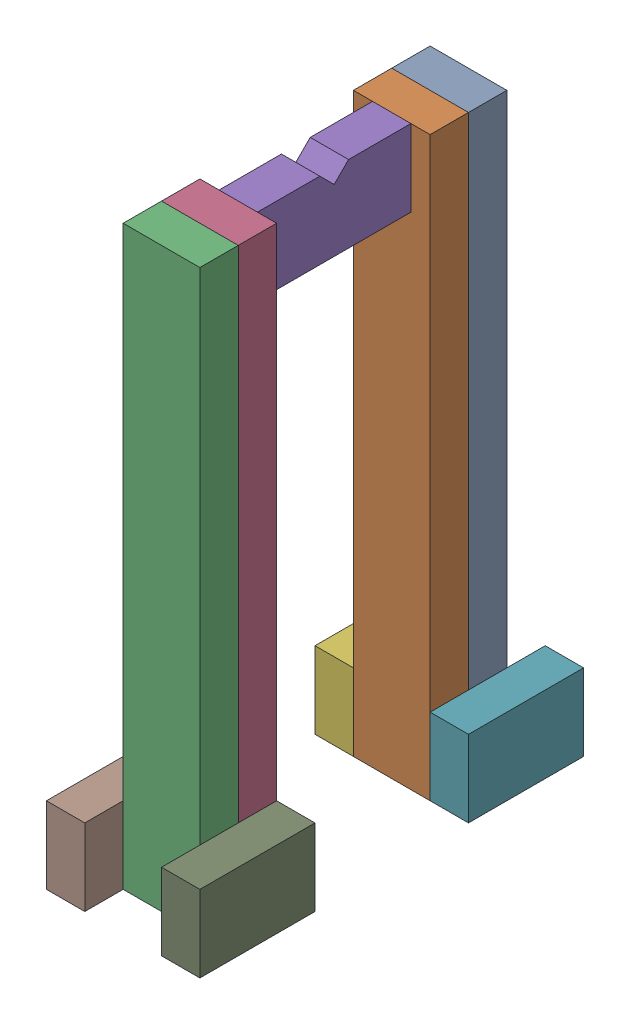
SolidWorks assembly RearRollHoop_CupJig, configuration Default. Lengths in mm.
Overall size (203.2 763.79 508).
9 component instances, 3 part files, 24 mates.
Components (placement in the parent):
- 30.028_Leg_CupJig_002-1: 30.028_Leg_CupJig_002 [Default] at origin size (101.6 763.79 50.8)
- 30.028_Leg_CupJig_002-2: 30.028_Leg_CupJig_002 [Default] at (0 0 50.8) size (101.6 763.79 50.8)
- 30.028_Leg_CupJig_002-3: 30.028_Leg_CupJig_002 [Default] at (0 0 355.6) size (101.6 763.79 50.8)
- 30.028_Leg_CupJig_002-4: 30.028_Leg_CupJig_002 [Default] at (0 0 304.8) size (101.6 763.79 50.8)
- 30.028_Cup_CupJig_002-1: 30.028_Cup_CupJig_002 [Default] at (50.8 662.194 279.4) x (0 0 -1) z (1 0 0) size (203.2 101.6 50.8)
- LegBase_CupJig_002-1: LegBase_CupJig_002 [Default] at (-25.4 0 -76.2) x (0 0 1) z (-1 0 0) size (152.4 101.6 50.8)
- LegBase_CupJig_002-2: LegBase_CupJig_002 [Default] at (127 0 76.2) x (0 0 -1) z (1 0 0) size (152.4 101.6 50.8)
- LegBase_CupJig_002-3: LegBase_CupJig_002 [Default] at (-25.4 0 431.8) x (0 0 -1) z (1 0 0) size (152.4 101.6 50.8)
- LegBase_CupJig_002-4: LegBase_CupJig_002 [Default] at (127 0 279.4) x (0 0 1) z (-1 0 0) size (152.4 101.6 50.8)
Mates (geometry in assembly coordinates):
- Coincident1: coincident anti-aligned: plane of 30.028_Leg_CupJig_002-1 through (0 0 25.4) normal (0 0 1); plane of 30.028_Leg_CupJig_002-2 through (0 0 25.4) normal (0 0 -1)
- Coincident2: coincident aligned: plane of 30.028_Leg_CupJig_002-1 through (101.6 0 25.4) normal (1 0 0); plane of 30.028_Leg_CupJig_002-2 through (101.6 0 76.2) normal (1 0 0)
- Coincident3: coincident aligned: plane of 30.028_Leg_CupJig_002-1 through (0 763.794 25.4) normal (0 1 0); plane of 30.028_Leg_CupJig_002-2 through (0 763.794 76.2) normal (0 1 0)
- Coincident4: coincident anti-aligned: plane of 30.028_Leg_CupJig_002-2 through (0 0 76.2) normal (0 0 1); plane of 30.028_Cup_CupJig_002-1 through (76.2 662.194 76.2) normal (0 0 -1)
- Width1: width anti-aligned: plane of 30.028_Leg_CupJig_002-2 through (101.6 0 76.2) normal (1 0 0); plane of 30.028_Cup_CupJig_002-1 through (0 0 76.2) normal (-1 0 0); plane of 30.028_Leg_CupJig_002-2 through (25.4 662.194 279.4) normal (-1 0 0); plane of 30.028_Cup_CupJig_002-1 through (76.2 662.194 279.4) normal (1 0 0)
- Coincident5: coincident aligned: plane of 30.028_Leg_CupJig_002-2 through (0 763.794 76.2) normal (0 1 0); plane of 30.028_Cup_CupJig_002-1 through (76.2 763.794 158.75) normal (0 1 0)
- Coincident6: coincident anti-aligned: plane of 30.028_Leg_CupJig_002-3 through (0 0 330.2) normal (0 0 -1); plane of 30.028_Leg_CupJig_002-4 through (0 0 330.2) normal (0 0 1)
- Coincident7: coincident aligned: plane of 30.028_Leg_CupJig_002-3 through (101.6 0 381) normal (1 0 0); plane of 30.028_Leg_CupJig_002-4 through (101.6 0 330.2) normal (1 0 0)
- Coincident8: coincident aligned: plane of 30.028_Leg_CupJig_002-3 through (0 763.794 381) normal (0 1 0); plane of 30.028_Leg_CupJig_002-4 through (0 763.794 330.2) normal (0 1 0)
- Width2: width anti-aligned: plane of 30.028_Leg_CupJig_002-4 through (101.6 0 330.2) normal (1 0 0); plane of 30.028_Cup_CupJig_002-1 through (0 0 330.2) normal (-1 0 0); plane of 30.028_Leg_CupJig_002-4 through (25.4 662.194 279.4) normal (-1 0 0); plane of 30.028_Cup_CupJig_002-1 through (76.2 662.194 279.4) normal (1 0 0)
- Coincident9: coincident anti-aligned: plane of 30.028_Cup_CupJig_002-1 through (76.2 662.194 279.4) normal (0 0 1); plane of 30.028_Leg_CupJig_002-4 through (0 0 279.4) normal (0 0 -1)
- Coincident10: coincident aligned: plane of 30.028_Cup_CupJig_002-1 through (76.2 763.794 279.4) normal (0 1 0); plane of 30.028_Leg_CupJig_002-4 through (0 763.794 330.2) normal (0 1 0)
- Coincident11: coincident anti-aligned: plane of 30.028_Leg_CupJig_002-3 through (101.6 0 381) normal (1 0 0); plane of LegBase_CupJig_002-4 through (101.6 0 279.4) normal (-1 0 0)
- Coincident12: coincident aligned: plane of 30.028_Leg_CupJig_002-4 through (0 0 279.4) normal (0 0 -1); plane of LegBase_CupJig_002-4 through (101.6 0 279.4) normal (0 0 -1)
- Coincident13: coincident aligned: plane of 30.028_Leg_CupJig_002-4 through (0 0 330.2) normal (0 -1 0); plane of LegBase_CupJig_002-4 through (101.6 0 279.4) normal (0 -1 0)
- Coincident14: coincident anti-aligned: plane of 30.028_Leg_CupJig_002-2 through (101.6 0 76.2) normal (1 0 0); plane of LegBase_CupJig_002-2 through (101.6 0 76.2) normal (-1 0 0)
- Coincident15: coincident aligned: plane of 30.028_Leg_CupJig_002-2 through (0 0 76.2) normal (0 0 1); plane of LegBase_CupJig_002-2 through (152.4 0 76.2) normal (0 0 1)
- Coincident16: coincident aligned: plane of 30.028_Leg_CupJig_002-1 through (0 0 25.4) normal (0 -1 0); plane of LegBase_CupJig_002-2 through (152.4 0 76.2) normal (0 -1 0)
- Coincident17: coincident anti-aligned: plane of 30.028_Leg_CupJig_002-3 through (0 0 381) normal (-1 0 0); plane of LegBase_CupJig_002-3 through (0 0 431.8) normal (1 0 0)
- Coincident18: coincident aligned: plane of 30.028_Leg_CupJig_002-4 through (0 0 279.4) normal (0 0 -1); plane of LegBase_CupJig_002-3 through (0 0 279.4) normal (0 0 -1)
- Coincident19: coincident aligned: plane of 30.028_Leg_CupJig_002-4 through (0 0 330.2) normal (0 -1 0); plane of LegBase_CupJig_002-3 through (0 0 431.8) normal (0 -1 0)
- Coincident20: coincident anti-aligned: plane of 30.028_Leg_CupJig_002-2 through (0 0 76.2) normal (-1 0 0); plane of LegBase_CupJig_002-1 through (0 0 -76.2) normal (1 0 0)
- Coincident21: coincident aligned: plane of 30.028_Leg_CupJig_002-2 through (0 0 76.2) normal (0 0 1); plane of LegBase_CupJig_002-1 through (-50.8 0 76.2) normal (0 0 1)
- Coincident22: coincident aligned: plane of 30.028_Leg_CupJig_002-2 through (0 0 76.2) normal (0 -1 0); plane of LegBase_CupJig_002-1 through (-50.8 0 -76.2) normal (0 -1 0)
